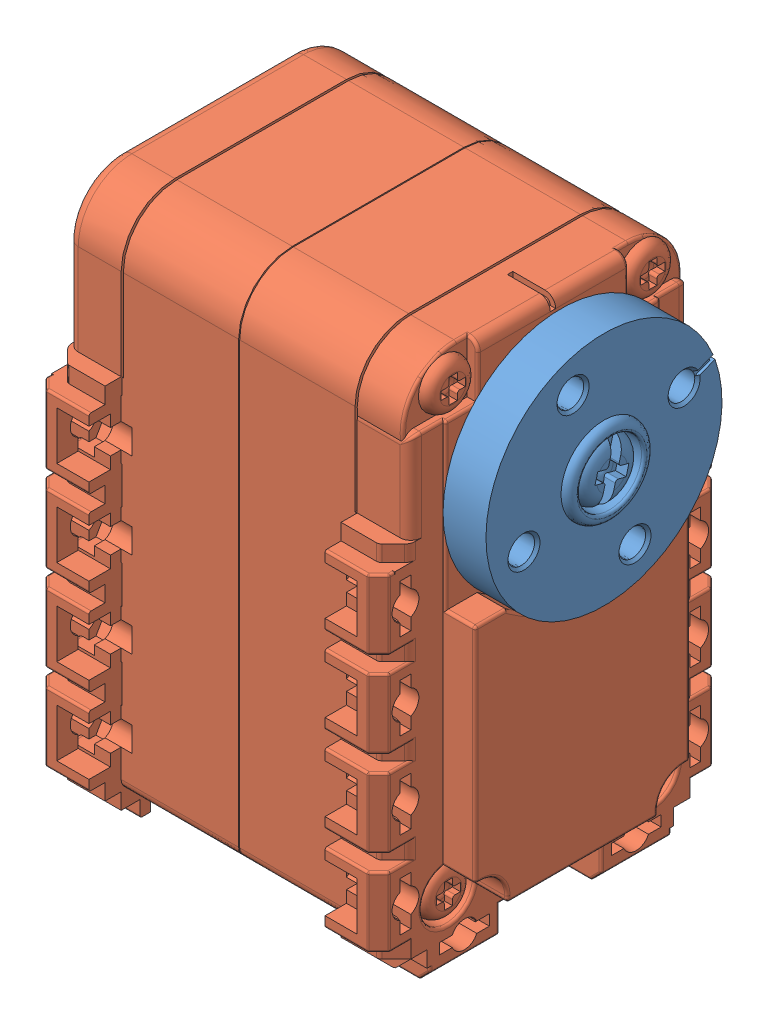
SolidWorks assembly AX12 Servo, configuration Default. Lengths in mm.
Overall size (40.85 52.72 32).
2 component instances, 2 part files, 2 mates.
Components (placement in the parent):
- ax12_wheel-1: ax12_wheel [Default] at (44.532 15.8309 -11.4342) x (0 0.360476 -0.932769) z (0 -0.932769 -0.360476) size (22 14.85 22)
- ax12_box-1: ax12_box [Default] at (25.532 3.8309 -11.4342) x (0 -1 0) z (0 0 -1) size (50 38.01 32)
Mates (geometry in assembly coordinates):
- Concentric1: concentric aligned: cylinder of ax12_wheel-1 through (32.532 15.8309 -11.4342) axis (1 0 0) radius 3; cylinder of ax12_box-1 through (32.532 15.8309 -11.4342) axis (1 0 0) radius 3
- Coincident1: coincident anti-aligned: plane of ax12_wheel-1 through (32.532 15.8309 -11.4342) normal (-1 0 0); plane of ax12_box-1 through (32.532 15.8309 -11.4342) normal (1 0 0)
